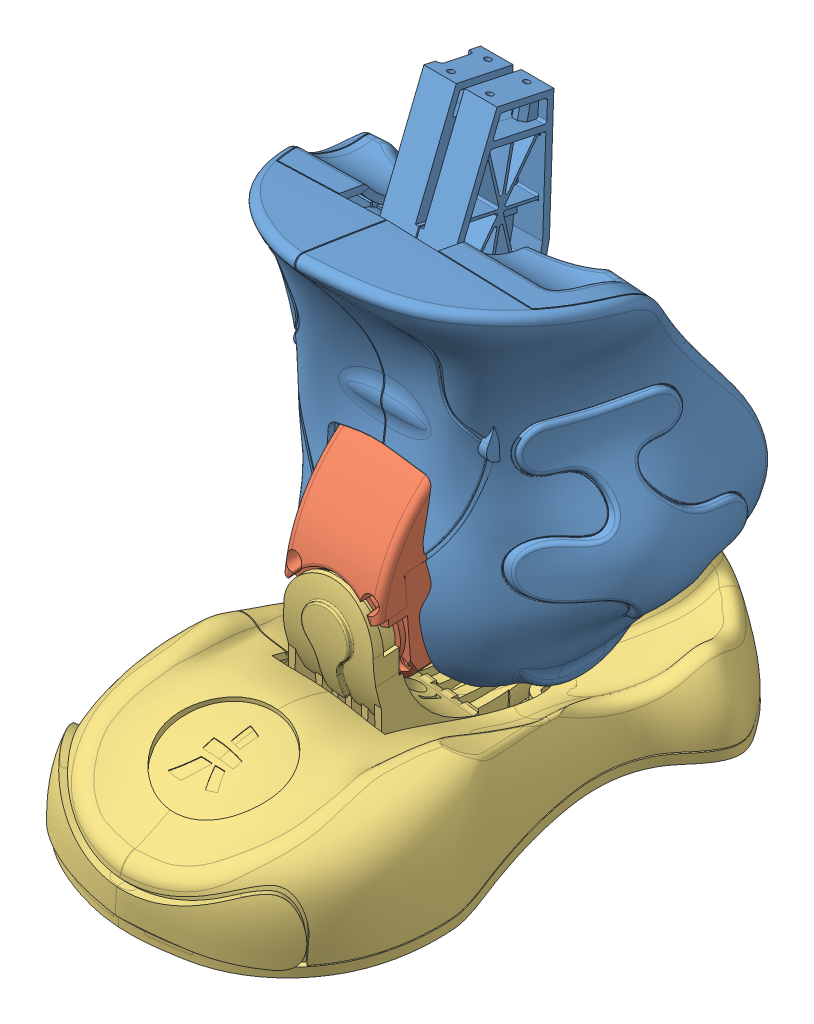
SolidWorks assembly Assemblage4, configuration Défaut. Lengths in mm.
Overall size (115.93 183.61 176.52).
3 component instances, 3 part files, 4 mates.
Components (placement in the parent):
- Tibia-1: Tibia [Default] at (-16.7652 3.7608 145.0833) size (102.54 151.12 111.07)
- Ankle-2: Ankle [Default] at (-16.7652 -39.0658 219.1048) x (1 0 0) z (0 0.075667 -0.997133) size (43 61.38 84.83)
- Foot-1: Foot [Default] at (-21.8314 -81.366 148.4014) x (0.993675 -0.111976 -0.008497) z (0 -0.075667 0.997133) size (106.44 58.74 171.69)
Mates (geometry in assembly coordinates):
- Coaxiale1: concentric anti-aligned: cylinder of Tibia-1 through (-36.4652 -36.5143 149.7992) axis (1 0 0) radius 8.5; cylinder of Ankle-2 through (2.8348 -36.5143 149.7992) axis (-1 0 0) radius 7.5
- Largeur1: width aligned: plane of Ankle-2 through (-30.8652 -7.2771 127.9488) normal (-1 0 0); plane of Tibia-1 through (-2.6652 -44.6363 125.1138) normal (1 0 0); plane of Ankle-2 through (-2.0652 -11.9376 73.3287) normal (-1 0 0); plane of Tibia-1 through (-31.4652 -11.9376 73.3287) normal (1 0 0)
- Coaxiale2: concentric aligned: cylinder of Ankle-2 through (-16.7652 -33.6843 112.5064) axis (0 -0.075667 0.997133) radius 5; cylinder of Foot-1 through (-16.7652 -33.8508 114.7001) axis (0 -0.075667 0.997133) radius 6
- Coïncidente1: coincident anti-aligned: plane of Ankle-2 through (-16.7652 -34.214 119.4863) normal (0 0.075667 -0.997133); plane of Foot-1 through (-16.7652 -34.214 119.4863) normal (0 -0.075667 0.997133)
